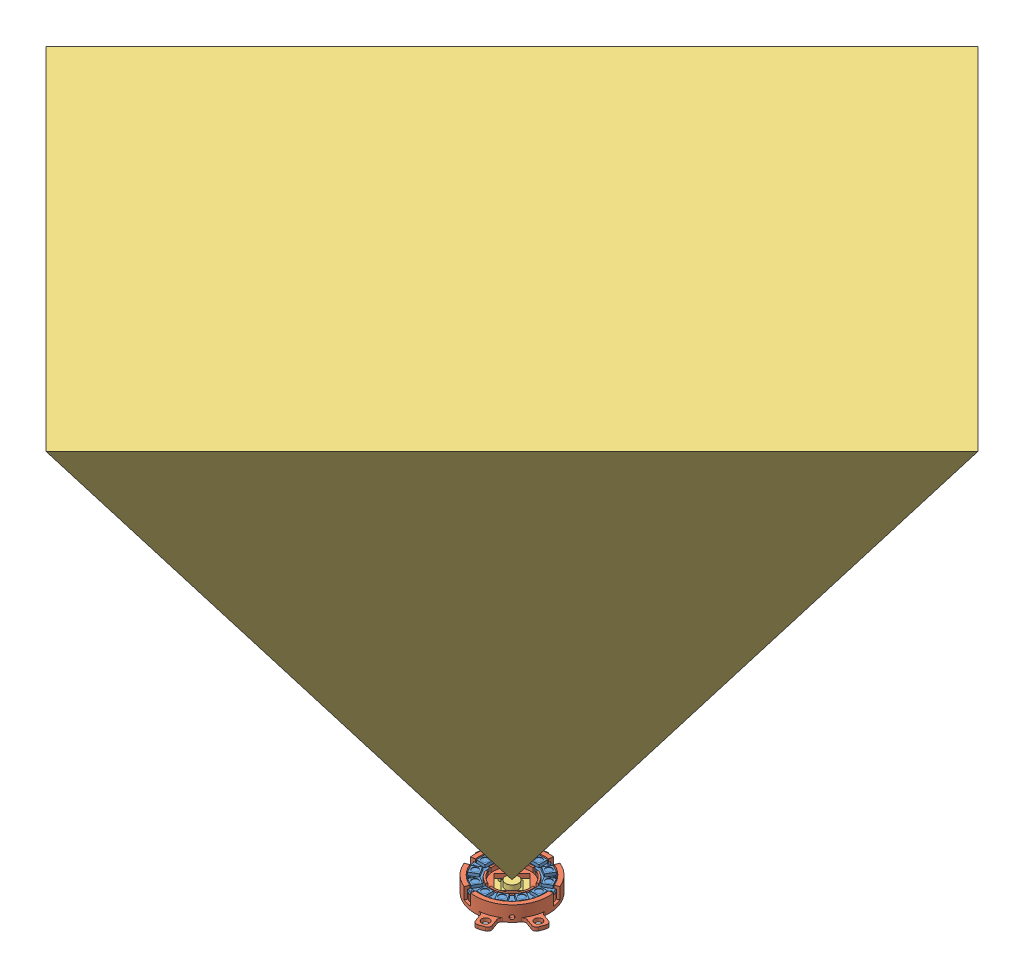
SolidWorks assembly camera_LEDring_with_casing, configuration Default. Lengths in mm.
Overall size (53.77 11.34 53.77).
3 component instances, 3 part files, 8 mates.
Components (placement in the parent):
- camera_LEDring-1: camera_LEDring [Default] at (0 0 0.2599) size (37 3.15 37)
- camera_LEDring_casing-1: camera_LEDring_casing [Default] x (0 0 -1) z (1 0 0) size (53.77 8.34 53.77)
- picamera-1: picamera [Default] at (-2.2981 -6 15.6395) x (0.707107 0 -0.707107) z (0.707107 0 0.707107) size (361.94 309 272.17)
Mates (geometry in assembly coordinates):
- InPlace1: in place: plane of camera_LEDring_casing-1 through (0 0 0) normal (1 0 0); moOrthogonalPlaneRef_w of camera_LEDring_casing-1 through (0 0 0) normal (0 1 0); plane of camera_LEDring_casing-1 through (0 0 0) normal (0 0 -1); unknown of camera_LEDring_casing-1
- Coincident1: coincident aligned: 
- Coincident2: coincident aligned: plane of camera_LEDring_casing-1 through (0 0 0) normal (0 1 0)
- Coincident3: coincident anti-aligned: plane of camera_LEDring_casing-1 through (0 0 0) normal (0 0 -1)
- Concentric1: concentric aligned: cylinder of camera_LEDring_casing-1 through (0 -998.45 0.2599) axis (0 -1 0) radius 20.2; cylinder of picamera-1 through (0 16.8995 0.2599) axis (0 -1 0) radius 3.5
- Coincident5: coincident anti-aligned: plane of picamera-1 through (-2.2981 -5 15.6395) normal (0 1 0); plane of camera_LEDring_casing-1 through (0 -5 0) normal (0 -1 0)
- Parallel1: parallel anti-aligned: plane of camera_LEDring-1 through (-11.5789 6.75 -10.7886) normal (0.707107 0 0.707107); plane of picamera-1 through (-6.0104 -2 0.2599) normal (-0.707107 0 -0.707107)
- Coincident6: coincident anti-aligned: plane of camera_LEDring-1 through (0 0 0.2599) normal (0 -1 0)
